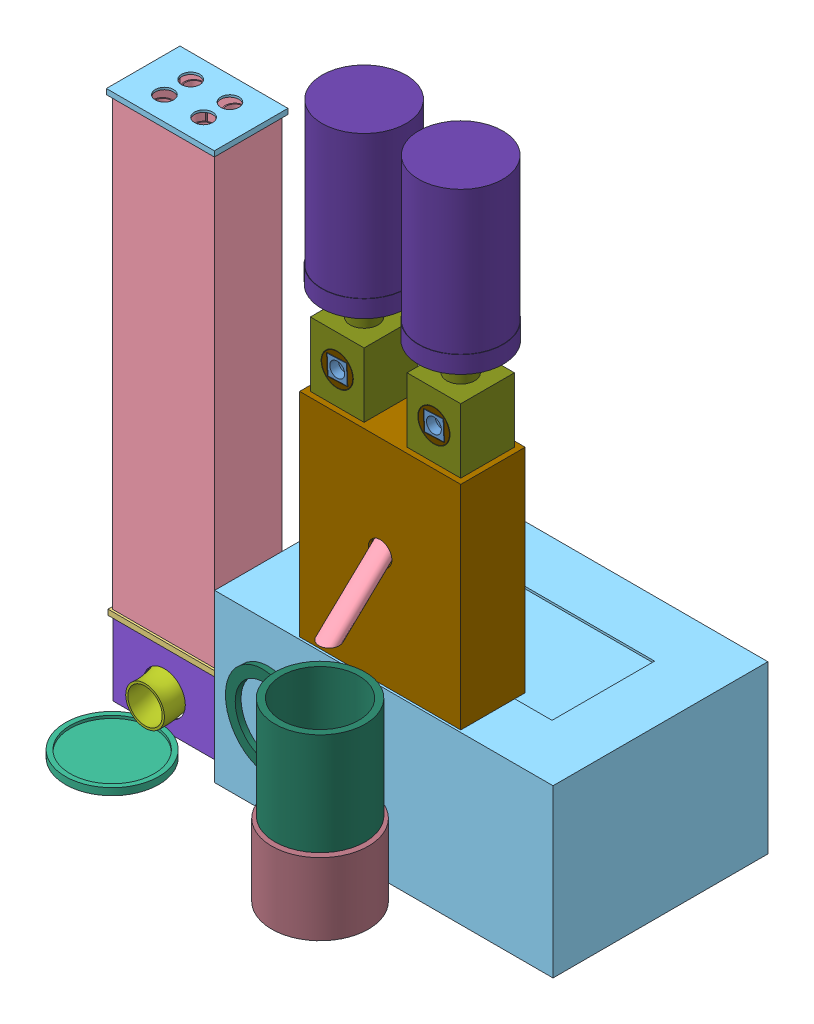
SolidWorks assembly EnsamblajeFinal, configuration Predeterminado. Lengths in mm.
Overall size (432.03 588.5 302.76).
72 component instances, 44 part files, 20 mates.
Components (placement in the parent):
- Ensamblaje1-1: Ensamblaje1 [Predeterminado] at (-124.7886 43.336 481.009) x (0 0 -1) z (1 0 0) size (68.5 429 102)
  - ServosConTubos-1: ServosConTubos [Predeterminado] at (2.491 9.9258 73.5) size (49 4 78)
  - UnionTubos-1: UnionTubos [Predeterminado] at (2.491 9.9258 75.55) x (-1 0 0) z (0 0 1) size (49 40.94 58.1)
  - Servo-1: Servo [Predeterminado] at (2.741 -2.0742 52.75) size (12 30.1 32.5)
  - Servo-2: Servo [Predeterminado] at (2.741 -2.0742 91.25) size (12 30.1 32.5)
  - Acrilico-1: Acrilico [Predeterminado] at (1.741 -24.0149 74.8) x (-1 0 0) z (0 0 -1) size (63 420 95)
  - ServosConTubos-2: ServosConTubos [Predeterminado] at (2.491 75.8429 73.5) x (-1 0 0) z (0 0 1) size (49 4 78)
  - Servo-3: Servo [Predeterminado] at (2.241 87.8429 52.75) x (-1 0 0) z (0 0 1) size (12 30.1 32.5)
  - Servo-4: Servo [Predeterminado] at (2.241 87.8429 91.25) x (-1 0 0) z (0 0 1) size (12 30.1 32.5)
  - SoporteTubos-1: SoporteTubos [Predeterminado] at (-5.259 395.9851 62.8) size (68.5 5 100.5)
  - TubosMedio-1: TubosMedio [Predeterminado] at (2.491 53.6258 73.5) size (49 2 78)
  - Perno-1: Perno [Predeterminado] at (21.991 75.8429 41.5) size (8.7 78.2 8.7)
  - Perno-2: Perno [Predeterminado] at (-17.009 75.8429 41.5) size (8.7 78.2 8.7)
  - Perno-3: Perno [Predeterminado] at (21.991 75.8429 109.5) x (0.404197 0 -0.914672) z (0.914672 0 0.404197) size (8.7 78.2 8.7)
  - Perno-4: Perno [Predeterminado] at (-17.009 75.8429 109.5) x (-0.888519 0 0.45884) z (-0.45884 0 -0.888519) size (8.7 78.2 8.7)
  - PastillaAmarrillaAjuste-1: PastillaAmarrillaAjuste [Predeterminado] at (-12.009 64.3429 94.6) x (0 0 1) z (-1 0 0) size (20 15.85 18)
  - PernoTuerca-1: PernoTuerca [Predeterminado] at (-17.009 6.4258 41.5) x (0.998119 0 0.061298) z (-0.061298 0 0.998119) size (9.5 3.5 10.97)
  - PernoTuerca-2: PernoTuerca [Predeterminado] at (21.991 6.4258 109.5) size (9.5 3.5 10.97)
  - PernoTuerca-3: PernoTuerca [Predeterminado] at (-17.009 6.4258 109.5) x (0.996539 0 -0.083129) z (0.083129 0 0.996539) size (9.5 3.5 10.97)
  - PernoTuerca-4: PernoTuerca [Predeterminado] at (21.991 6.4258 41.5) size (9.5 3.5 10.97)
  - TuboMedioAmarrillo-1: TuboMedioAmarrillo [Predeterminado] at (-12.009 29.6258 94.6) x (0.872551 0 -0.488522) z (0.488522 0 0.872551) size (14.5 26 14.5)
  - PastillaAmarrillaAjuste-2: PastillaAmarrillaAjuste [Predeterminado] at (-12.009 21.4258 94.6) x (0 0 -1) z (-1 0 0) size (20 15.85 18) (hidden)
  - PastillaBlancaAjuste-2: PastillaBlancaAjuste [Predeterminado] at (16.991 21.4258 94.6) x (0 0 1) z (1 0 0) size (20 20.07 18) (hidden)
  - TuboMedioBlanco-1: TuboMedioBlanco [Predeterminado] at (16.991 34.1258 94.6) x (0.999102 0 -0.042366) z (0.042366 0 0.999102) size (12.5 21.5 12.5)
  - PastillaBlancaAjuste2-1: PastillaBlancaAjuste2 [Predeterminado] at (16.991 64.3429 94.6) x (0 0 -1) z (1 0 0) size (20 15.53 18)
  - PastillaNaranjaAjuste-1: PastillaNaranjaAjuste [Predeterminado] at (16.991 64.3429 56.5) x (0 0 -1) z (1 0 0) size (20 15.72 18)
  - TuboMedioNaranja-1: TuboMedioNaranja [Predeterminado] at (16.991 36.1258 56.5) size (15 19.5 15)
  - TuboMedioAzul-1: TuboMedioAzul [Predeterminado] at (-12.009 36.1258 56.5) x (-0.835913 0 0.548862) z (-0.548862 0 -0.835913) size (13 19.5 13)
  - PastillaAzulAjuste-1: PastillaAzulAjuste [Predeterminado] at (-12.009 64.3429 56.5) x (0 0 1) z (-1 0 0) size (20 15.56 18)
  - PastillaAzulAjuste2-1: PastillaAzulAjuste2 [Predeterminado] at (-12.009 21.4258 56.5) x (0 0 -1) z (-1 0 0) size (20 21.94 18) (hidden)
  - PastillaNaranjaAjuste2-1: PastillaNaranjaAjuste2 [Predeterminado] at (16.991 21.4258 56.5) x (0 0 1) z (1 0 0) size (20 21.97 18) (hidden)
  - BrazoServo-1: BrazoServo [Predeterminado] at (2.241 60.4429 58) x (-0.995394 0 -0.095869) z (-0.095869 0 0.995394) size (32 3.7 7)
  - BrazoServo-2: BrazoServo [Predeterminado] at (2.741 24.9258 96.5) x (-0.997904 0 0.064708) z (-0.064708 0 -0.997904) size (32 3.7 7)
  - BrazoServo-3: BrazoServo [Predeterminado] at (2.741 24.9258 58) x (0.995023 0 0.099648) z (-0.099648 0 0.995023) size (32 3.7 7)
  - BrazoServo-4: BrazoServo [Predeterminado] at (2.241 60.4429 96.5) x (0.984587 0 -0.174895) z (-0.174895 0 -0.984587) size (32 3.7 7)
  - BrazoExtension-3: BrazoExtension [Predeterminado] at (-17.4422 56.7429 55.1529) x (0.999799 0 -0.020027) z (0.020027 0 0.999799) size (40.04 0.5 23.31)
  - BrazoExtension_AN-2: BrazoExtension_AN [Predeterminado] at (-17.1441 27.6258 96.8413) x (0.983694 0 -0.179852) z (0.179852 0 0.983694) size (40.03 7 27.06)
  - BrazoExtension-4: BrazoExtension [Predeterminado] at (-17.4838 56.2429 99.0428) x (0.957704 0 -0.287755) z (0.287755 0 0.957704) size (40.04 0.5 23.31)
  - BrazoExtension_AB-1: BrazoExtension_AB [Predeterminado] at (22.6018 35.1258 59.0381) x (-0.976785 0 -0.214224) z (-0.214224 0 0.976785) size (41.06 7.5 20.68)
  - TapaInferiorCaja-1: TapaInferiorCaja [Predeterminado] at (10.241 -24.0149 64.3) x (-1 0 0) z (0 0 1) size (68.5 5 100.5)
  - tuboreserva-1: tuboreserva [Predeterminado] at (-12.009 75.8429 56.5) x (0.395358 0 -0.918527) z (0.918527 0 0.395358) size (18 315 18)
  - tuboreserva-2: tuboreserva [Predeterminado] at (-12.009 75.8429 94.6) x (0.85234 0 -0.522988) z (0.522988 0 0.85234) size (18 315 18)
  - tuboreserva-3: tuboreserva [Predeterminado] at (16.991 75.8429 56.5) x (0.294164 0 -0.955755) z (0.955755 0 0.294164) size (18 315 18)
  - tuboreserva-4: tuboreserva [Predeterminado] at (16.991 75.8429 94.6) x (0.996074 0 -0.088521) z (0.088521 0 0.996074) size (18 315 18)
- TanqueDeAgua-1: TanqueDeAgua [Predeterminado] at (173.5421 -51.6789 429) size (315 155 200)
- BatidorMagnetico-1: BatidorMagnetico [Predeterminado] at (160.8094 -51.6789 575.6437) x (0 0 -1) z (1 0 0) size (97 69 87) (hidden)
- Plato-1: Plato [Predeterminado] at (-49.3483 -49.1789 559.0262) x (0.997972 0 -0.063658) z (0.063658 0 0.997972) size (87 9 87)
- TuboFinal-1: TuboFinal [Predeterminado] at (-49.2386 -22.6789 528.518) x (0 1 0) z (-1 0 0) size (60.93 68 36)
- SoporteMecanismoPastillas-1: SoporteMecanismoPastillas [Predeterminado] at (-49.2386 -51.6789 478.518) size (96 70 64)
- SoporteMecanismoPowder-1: SoporteMecanismoPowder [Predeterminado] at (213.131 298.3211 497) size (150 198 60)
- EnsamblajeBatidor-1: EnsamblajeBatidor [Predeterminado] at (172.6319 -66.6904 528.5476) x (0.999968 0 -0.008001) z (0.008001 0 0.999968) size (111.35 67 111.35)
  - SoporteMotor-1: SoporteMotor [Predeterminado] at (-12.199 19.6116 47) size (31.8 22 31.8)
  - Motor-1: Motor [Predeterminado] at (-12.199 29.1116 47) x (0.949438 0 -0.313954) z (0.313954 0 0.949438) size (30 47.9 30)
  - SoporteImanes-1: SoporteImanes [Predeterminado] at (-12.199 72.0116 47) x (-0.28831 0 -0.957537) z (0.957537 0 -0.28831) size (50 5 50)
  - TapaBatidor-1: TapaBatidor [Predeterminado] at (-12.199 15.0116 47) x (-0.276151 0 -0.961114) z (0.961114 0 -0.276151) size (90 67 90)
  - BaseBatido-1: BaseBatido [Predeterminado] at (-12.199 19.6116 47) x (0.876966 0 0.480553) z (-0.480553 0 0.876966) size (81 4 81)
- Taza-1: Taza [Predeterminado] at (160.8094 17.2211 575.6437) x (0.99629 0 0.086063) z (-0.086063 0 0.99629) size (132.84 95 84)
- EnsamblajePowderConEstructura-1: EnsamblajePowderConEstructura [Predeterminado] at (162.3058 343.6253 251.5) size (171.88 376.5 126.22)
  - EnsamblajePowderDispenser-1: EnsamblajePowderDispenser [Predeterminado] at (-46.3974 -19.9468 185.5) size (81.88 245.5 81.88)
    - CajaDelMedio-1: CajaDelMedio [Predeterminado] at (7.2227 -22.3574 60) size (50 91.5 50)
    - Botella-1: Botella [Predeterminado] at (7.2227 23.1426 60) x (0.999311 0 0.037103) z (-0.037103 0 0.999311) size (79 190 79)
    - CilindroCentral-1: CilindroCentral [Predeterminado] at (7.2227 7.6426 39) x (0 0 1) z (-0.043 0.999075 0) size (46 29 29)
    - CuadradoTorque-1: CuadradoTorque [Predeterminado] at (7.2227 7.6426 75) x (-0.999075 -0.043 0) z (0 0 1) size (18 18 10)
    - EjeSoporte-1: EjeSoporte [Predeterminado] at (7.2227 7.6426 33) x (1 0 0) z (0 -1 0) size (12 14 12)
  - PowderTuboFinal1DOS-1: PowderTuboFinal1DOS [Predeterminado] at (50.8253 -52.3042 245.5) size (122 65 32)
  - PowderTuboFinal2-1: PowderTuboFinal2 [Predeterminado] at (5.4246 -123.3042 261.0585) x (0.025741 0 -0.999669) z (0.999669 0 0.025741) size (94.57 81 19)
  - EnsamblajePowderDispenser-3: EnsamblajePowderDispenser [Predeterminado] at (43.6026 -19.9468 185.5) size (81.88 245.5 81.88)
    - CajaDelMedio-1: CajaDelMedio [Predeterminado] at (7.2227 -22.3574 60) size (50 91.5 50)
    - Botella-1: Botella [Predeterminado] at (7.2227 23.1426 60) x (0.999311 0 0.037103) z (-0.037103 0 0.999311) size (79 190 79)
    - CilindroCentral-1: CilindroCentral [Predeterminado] at (7.2227 7.6426 39) x (0 0 1) z (-0.043 0.999075 0) size (46 29 29)
    - CuadradoTorque-1: CuadradoTorque [Predeterminado] at (7.2227 7.6426 75) x (-0.999075 -0.043 0) z (0 0 1) size (18 18 10)
    - EjeSoporte-1: EjeSoporte [Predeterminado] at (7.2227 7.6426 33) x (1 0 0) z (0 -1 0) size (12 14 12)
Mates (geometry in assembly coordinates):
- Coincidente1: coincident: plane of assembly; plane of assembly; plane of TanqueDeAgua-1 through (173.5421 -51.6789 429) normal (0 -1 0); plane of BatidorMagnetico-1 through (160.8094 -51.6789 575.6437) normal (0 -1 0)
- Paralelo1: parallel: plane of assembly; plane of assembly; plane of TanqueDeAgua-1 through (16.0421 103.3211 529) normal (0 0 1); plane of BatidorMagnetico-1 through (204.3094 17.3211 527.1437) normal (0 0 -1)
- Coincidente3: coincident: plane of assembly; plane of assembly; plane of TanqueDeAgua-1 through (173.5421 -51.6789 429) normal (0 -1 0); plane of Plato-1 through (-49.3483 -51.6789 559.0262) normal (0 -1 0)
- Distancia1: distance = 60 mm: plane of assembly; plane of assembly; plane of Plato-1 through (-49.3483 -42.6789 559.0262) normal (0 1 0); plane of Ensamblaje1-1/TapaInferiorCaja-1 through (-60.4886 17.3211 470.768) normal (0 -1 0)
- Coincidente7: coincident: plane of assembly; plane of assembly; plane of Ensamblaje1-1/TapaInferiorCaja-1 through (-60.4886 17.3211 470.768) normal (0 -1 0); plane of TuboFinal-1 through (-49.2386 17.3211 478.518) normal (0 1 0)
- Concéntrica2: concentric: cylinder of assembly; circle of assembly; cylinder of Ensamblaje1-1/UnionTubos-1 through (-49.2386 65.2476 478.518) axis (0 -1 0) radius 15; circle of TuboFinal-1
- Paralelo4: parallel: plane of assembly; plane of assembly; plane of TanqueDeAgua-1 through (16.0421 103.3211 529) normal (0 0 1); plane of TuboFinal-1 through (-49.2386 -22.6789 528.518) normal (0 0 1)
- Coincidente10: coincident: plane of assembly; plane of assembly; plane of TanqueDeAgua-1 through (173.5421 -51.6789 429) normal (0 -1 0); plane of SoporteMecanismoPastillas-1 through (-49.2386 -51.6789 478.518) normal (0 -1 0)
- Paralelo6: parallel: plane of assembly; plane of assembly; plane of Ensamblaje1-1/TapaInferiorCaja-1 through (1.0114 -104.3033 512.768) normal (1 0 0); plane of TanqueDeAgua-1 through (16.0421 103.3211 529) normal (-1 0 0)
- Concéntrica3: concentric: circle of assembly; cylinder of assembly; circle of TuboFinal-1; cylinder of SoporteMecanismoPastillas-1 through (-49.2386 13.3211 478.518) axis (0 1 0) radius 16
- Paralelo7: parallel: plane of assembly; plane of assembly; plane of Ensamblaje1-1/TapaInferiorCaja-1 through (-99.4886 -104.3033 444.268) normal (-1 0 0); plane of SoporteMecanismoPastillas-1 through (-1.2386 18.3211 510.518) normal (1 0 0)
- Coincidente23: coincident: plane of assembly; plane of assembly; plane of BatidorMagnetico-1 through (160.8094 -51.6789 575.6437) normal (0 -1 0); plane of EnsamblajeBatidor-1/TapaBatidor-1 through (160.8094 -51.6789 575.6437) normal (0 -1 0)
- Concéntrica11: concentric: circle of assembly; cylinder of assembly; circle of BatidorMagnetico-1; cylinder of EnsamblajeBatidor-1/TapaBatidor-1 through (160.8094 13.3211 575.6437) axis (0 -1 0) radius 45
- Coincidente24: coincident: plane of assembly; plane of assembly; plane of BatidorMagnetico-1 through (160.8094 17.2211 575.6437) normal (0 1 0); plane of Taza-1 through (160.8094 17.2211 575.6437) normal (0 -1 0)
- Concéntrica12: concentric: circle of assembly; cylinder of assembly; circle of BatidorMagnetico-1; cylinder of Taza-1 through (160.8094 112.2211 575.6437) axis (0 -1 0) radius 42
- Distancia4: distance = 2 mm: plane of assembly; plane of assembly; plane of SoporteMecanismoPowder-1 through (93.131 301.3211 527) normal (0 0 1); plane of TanqueDeAgua-1 through (16.0421 103.3211 529) normal (0 0 1)
- Concéntrica13: concentric: cylinder of assembly; cylinder of assembly; cylinder of SoporteMecanismoPowder-1 through (123.131 301.3211 497) axis (0 -1 0) radius 14; cylinder of EnsamblajePowderConEstructura-1/PowderTuboFinal1DOS-1 through (123.131 301.3211 497) axis (0 -1 0) radius 16
- Paralelo11: parallel: plane of assembly; plane of assembly; plane of SoporteMecanismoPowder-1 through (93.131 301.3211 527) normal (0 0 1); plane of EnsamblajePowderConEstructura-1/EnsamblajePowderDispenser-1/CajaDelMedio-1 through (98.131 361.3211 522) normal (0 0 1)
- Coincidente31: coincident: plane of SoporteMecanismoPowder-1 through (213.131 301.3211 497) normal (0 1 0); plane of EnsamblajePowderConEstructura-1/EnsamblajePowderDispenser-3/CajaDelMedio-1 through (213.131 301.3211 497) normal (0 -1 0)
- Coincidente32: coincident: plane of assembly; plane of assembly; plane of TanqueDeAgua-1 through (173.5421 103.3211 429) normal (0 1 0); plane of SoporteMecanismoPowder-1 through (213.131 103.3211 497) normal (0 -1 0)
